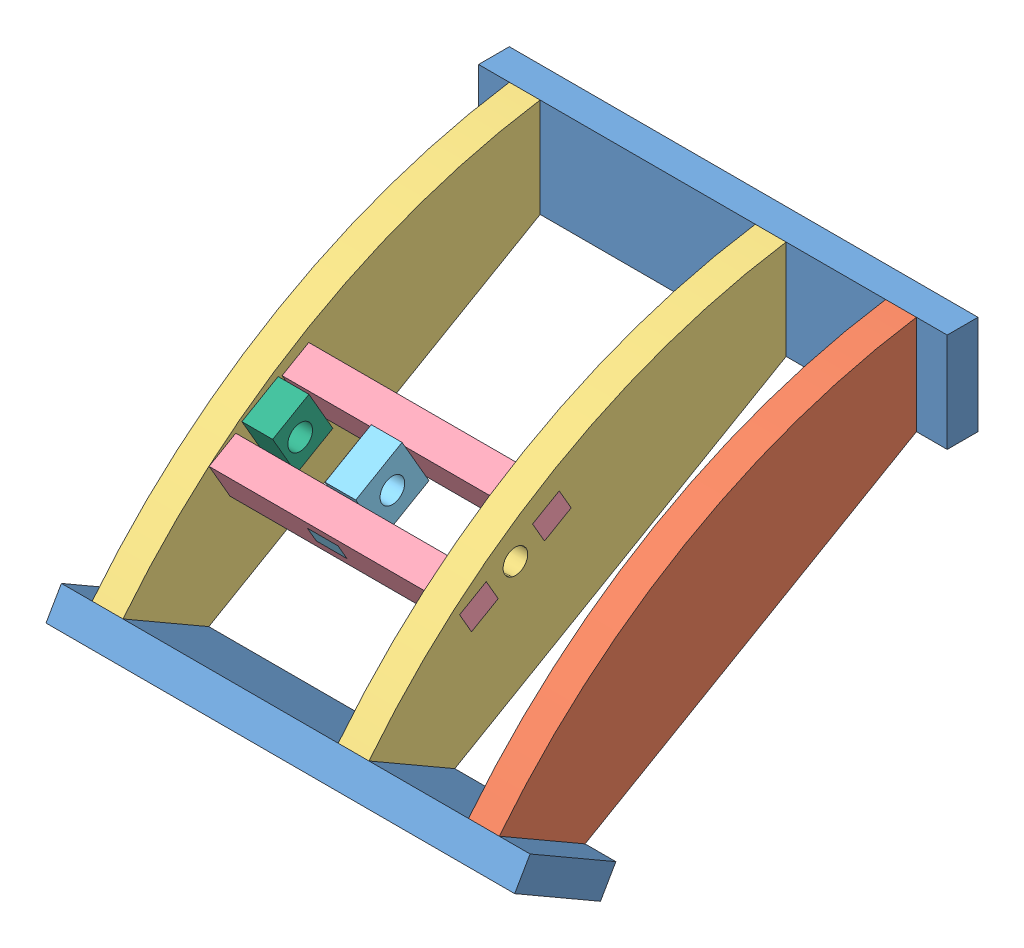
SolidWorks assembly Assem2, configuration Default. Lengths in mm.
Overall size (78.4 62.14 85.64).
9 component instances, 6 part files, 17 mates.
Components (placement in the parent):
- OuterActuatorSidePlate-1: OuterActuatorSidePlate [Default] at (-38.043 5.3284 -12.4367) size (78.4 16.58 5.15)
- SpanningPlate-1: SpanningPlate [Default] at (30.057 -86.882 -23.5738) x (0 0.5 -0.866025) z (1 0 0) size (86.18 22 5.15)
- ConnectingPlate-1: ConnectingPlate [Default] at (13.407 -86.882 -23.5738) x (0 -0.5 0.866025) z (-1 0 0) size (86.18 22 5.15)
- ConnectingPlate-2: ConnectingPlate [Default] at (-27.743 -86.882 -23.5738) x (0 -0.5 0.866025) z (-1 0 0) size (86.18 22 5.15)
- OuterActuatorSpanner-1: OuterActuatorSpanner [Default] at (-9.743 0.0713 27.9198) x (1 0 0) z (0 -0.5 0.866025) size (46.3 7 5.15)
- OuterActuatorSpanner-2: OuterActuatorSpanner [Default] at (-9.743 -6.9755 40.1253) x (1 0 0) z (0 -0.5 0.866025) size (46.3 7 5.15)
- SpacerBoltConnector-1: SpacerBoltConnector [Default] at (-12.318 -10.4166 44.0853) x (0 0.5 -0.866025) z (1 0 0) size (19.24 9 5.15)
- A-Spacer-1: A-Spacer [Default] at (-27.743 -3.1726 32.5384) x (0 0.866025 0.5) z (1 0 0) size (8 7 5.15)
- OuterActuatorSidePlate-2: OuterActuatorSidePlate [Default] at (-38.043 -26.6717 48.1391) x (1 0 0) z (0 -0.866025 0.5) size (78.4 16.58 5.15)
Mates (geometry in assembly coordinates):
- Coincident11: coincident anti-aligned: line of OuterActuatorSidePlate-1 through (-27.743 15.2746 -12.4367) axis (0 1 0); line of ConnectingPlate-2 through (-27.743 18.5901 -12.4367) axis (0 -1 0)
- Coincident12: coincident aligned: line of OuterActuatorSidePlate-1 through (-32.893 15.2746 -12.4367) axis (1 0 0); line of ConnectingPlate-2 through (-32.893 15.2746 -12.4367) axis (1 0 0)
- Coincident13: coincident anti-aligned: line of OuterActuatorSidePlate-1 through (13.407 15.2746 -12.4367) axis (0 1 0); line of ConnectingPlate-1 through (13.407 18.5901 -12.4367) axis (0 -1 0)
- Coincident14: coincident aligned: line of OuterActuatorSidePlate-1 through (8.257 15.2746 -12.4367) axis (1 0 0); line of ConnectingPlate-1 through (8.257 15.2746 -12.4367) axis (1 0 0)
- Coincident15: coincident aligned: line of OuterActuatorSidePlate-1 through (35.207 18.59 -12.4367) axis (-1 0 0); line of SpanningPlate-1 through (35.207 18.59 -12.4367) axis (-1 0 0)
- Coincident16: coincident aligned: line of OuterActuatorSidePlate-1 through (35.207 15.2746 -12.4367) axis (0 1 0); line of SpanningPlate-1 through (35.207 15.2746 -12.4367) axis (0 1 0)
- Coincident17: coincident anti-aligned: line of ConnectingPlate-2 through (-32.893 -1.2047 33.1298) axis (0 0.866025 0.5); line of OuterActuatorSpanner-1 through (-32.893 2.2594 35.1298) axis (0 -0.866025 -0.5)
- Coincident18: coincident anti-aligned: line of ConnectingPlate-2 through (-32.893 1.3703 28.6698) axis (0 -0.5 0.866025); line of OuterActuatorSpanner-1 through (-32.893 -1.2047 33.1298) axis (0 0.5 -0.866025)
- Coincident19: coincident aligned: line of ConnectingPlate-2 through (-32.893 -2.2124 42.8753) axis (0 -0.866025 -0.5); line of OuterActuatorSpanner-2 through (-32.893 -2.2124 42.8753) axis (0 -0.866025 -0.5)
- Coincident20: coincident anti-aligned: line of ConnectingPlate-2 through (-32.893 -5.6765 40.8753) axis (0 -0.5 0.866025); line of OuterActuatorSpanner-2 through (-32.893 -8.2515 45.3353) axis (0 0.5 -0.866025)
- Coincident22: coincident aligned: line of OuterActuatorSpanner-2 through (-12.318 -5.2204 47.0853) axis (0 -0.866025 -0.5); line of SpacerBoltConnector-1 through (-12.318 -5.2204 47.0853) axis (0 -0.866025 -0.5)
- Coincident23: coincident aligned: line of OuterActuatorSpanner-2 through (-7.168 -5.2204 47.0853) axis (-1 0 0); line of SpacerBoltConnector-1 through (-7.168 -5.2204 47.0853) axis (-1 0 0)
- Concentric1: concentric anti-aligned: cylinder of ConnectingPlate-2 through (-27.743 -1.7085 38.0026) axis (-1 0 0) radius 2.0675; cylinder of A-Spacer-1 through (-27.743 -1.7085 38.0026) axis (1 0 0) radius 2.0675
- Coincident24: coincident anti-aligned: plane of ConnectingPlate-2 through (-27.743 -86.882 -23.5738) normal (1 0 0); plane of A-Spacer-1 through (-27.743 -3.1726 32.5384) normal (-1 0 0)
- Parallel1: parallel aligned: plane of SpacerBoltConnector-1 through (-7.168 4.4242 36.3804) normal (0 0.866025 0.5); plane of A-Spacer-1 through (-22.593 3.7556 36.5384) normal (0 0.866025 0.5)
- Coincident26: coincident anti-aligned: line of ConnectingPlate-2 through (-32.893 -26.1586 59.3278) axis (0 0.5 0.866025); line of OuterActuatorSidePlate-2 through (-32.893 -24.5009 62.199) axis (0 -0.5 -0.866025)
- Coincident27: coincident aligned: line of ConnectingPlate-2 through (-32.893 -26.1586 59.3278) axis (1 0 0); line of OuterActuatorSidePlate-2 through (-32.893 -26.1586 59.3278) axis (1 0 0)
